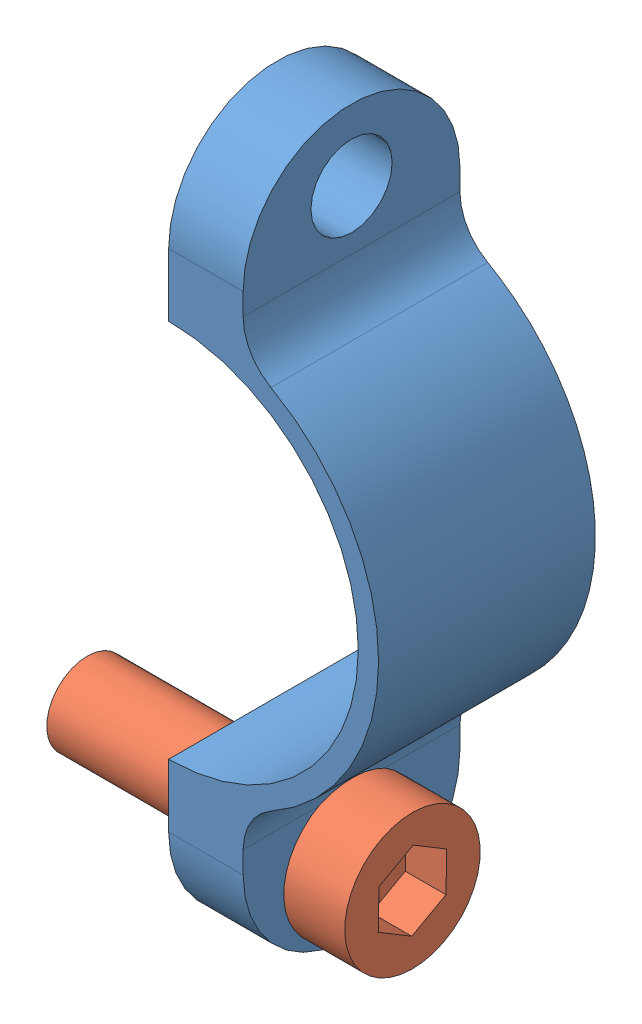
SolidWorks assembly PUTM-S-SF-RB_bearing_mount_assembly, configuration Domyślna. Lengths in mm.
Overall size (29.5 53.3 16).
2 component instances, 2 part files, 0 mates.
Components (placement in the parent):
- PUTM-S-SF-RB-bearing_mount-1: PUTM-S-SF-RB-bearing_mount [Domyślna] at (-0.5 -47.6728 -8) size (15.5 53.3 16)
- PUTM-S-SF-RB-Bolt-2: PUTM-S-SF-RB-Bolt [Domyślna] at (9.5 -69.0728 0) x (0 -0.0195 -0.99981) z (0 -0.99981 0.0195) size (10 24 10)
